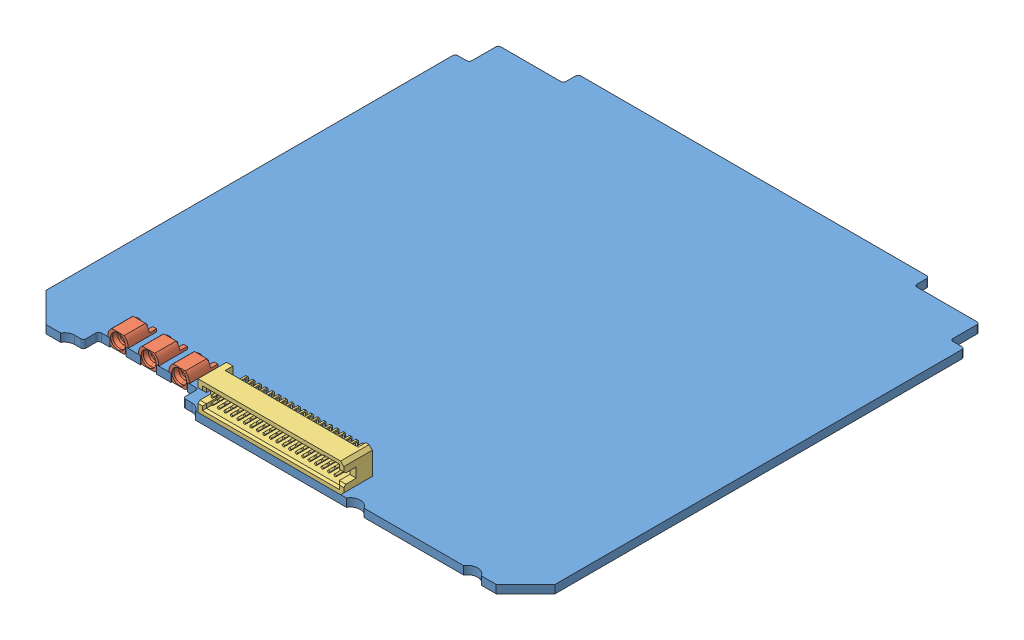
SolidWorks assembly C3Card, configuration Default. Lengths in mm.
Overall size (99.8 7.62 107.17).
5 component instances, 3 part files, 9 mates.
Components (placement in the parent):
- GenericCardPCBDefinition-1: GenericCardPCBDefinition [RF] at origin size (99.8 1.6 107.17)
- Molex, LLC 0733000020 (Card Connector)-1: Molex, LLC 0733000020 (Card Connector) [Default] at (-22 0.9778 40.8) size (3.99 3.17 5.61)
- TFM_120_01_L_D_RA_defeature-1: TFM_120_01_L_D_RA_defeature [Default] at (0 3.6575 39.237) x (1 0 0) z (0 -1 0) size (28.58 7.49 7.62)
- Molex, LLC 0733000020 (Card Connector)-2: Molex, LLC 0733000020 (Card Connector) [Default] at (-28 0.9778 40.8) size (3.99 3.17 5.61)
- Molex, LLC 0733000020 (Card Connector)-3: Molex, LLC 0733000020 (Card Connector) [Default] at (-34 0.9778 40.8) size (3.99 3.17 5.61)
Mates (geometry in assembly coordinates):
- Coincident1: coincident anti-aligned: plane of Molex, LLC 0733000020 (Card Connector)-1 through (-20.0061 0.8 40.8) normal (0 -1 0); plane of GenericCardPCBDefinition-1 through (0 0.8 0) normal (0 1 0)
- Coincident2: coincident aligned: plane of GenericCardPCBDefinition-1 through (0 -0.8 40.8) normal (0 0 1); plane of Molex, LLC 0733000020 (Card Connector)-1 through (-22 -0.6097 40.8) normal (0 0 1)
- Symmetric1: symmetric aligned: plane of GenericCardPCBDefinition-1 through (-20.41 -0.8 0) normal (-1 0 0); plane of Molex, LLC 0733000020 (Card Connector)-1 through (-23.59 -0.8 0) normal (1 0 0); plane of GenericCardPCBDefinition-1 through (-22 0.9778 40.8) normal (1 0 0)
- Coincident7: coincident: line of GenericCardPCBDefinition-1 through (0 0.8 -5.2282) axis (0 0 1); plane of TFM_120_01_L_D_RA_defeature-1 through (0 3.6575 39.237) normal (1 0 0)
- Coincident8: coincident anti-aligned: plane of GenericCardPCBDefinition-1 through (0 0.8 0) normal (0 1 0); plane of TFM_120_01_L_D_RA_defeature-1 through (-14.2875 0.8 44.825) normal (0 -1 0)
- Coincident9: coincident: line of GenericCardPCBDefinition-1 through (49.9 0.8 37.332) axis (-1 0 0); plane of TFM_120_01_L_D_RA_defeature-1 through (0 3.6575 37.332) normal (0 0 -1)
- Coincident10: coincident aligned: plane of GenericCardPCBDefinition-1 through (0 0 0) normal (0 0 1)
- Coincident11: coincident aligned: plane of GenericCardPCBDefinition-1 through (0 0 0) normal (0 1 0)
- Coincident12: coincident aligned: plane of GenericCardPCBDefinition-1 through (0 0 0) normal (1 0 0)
